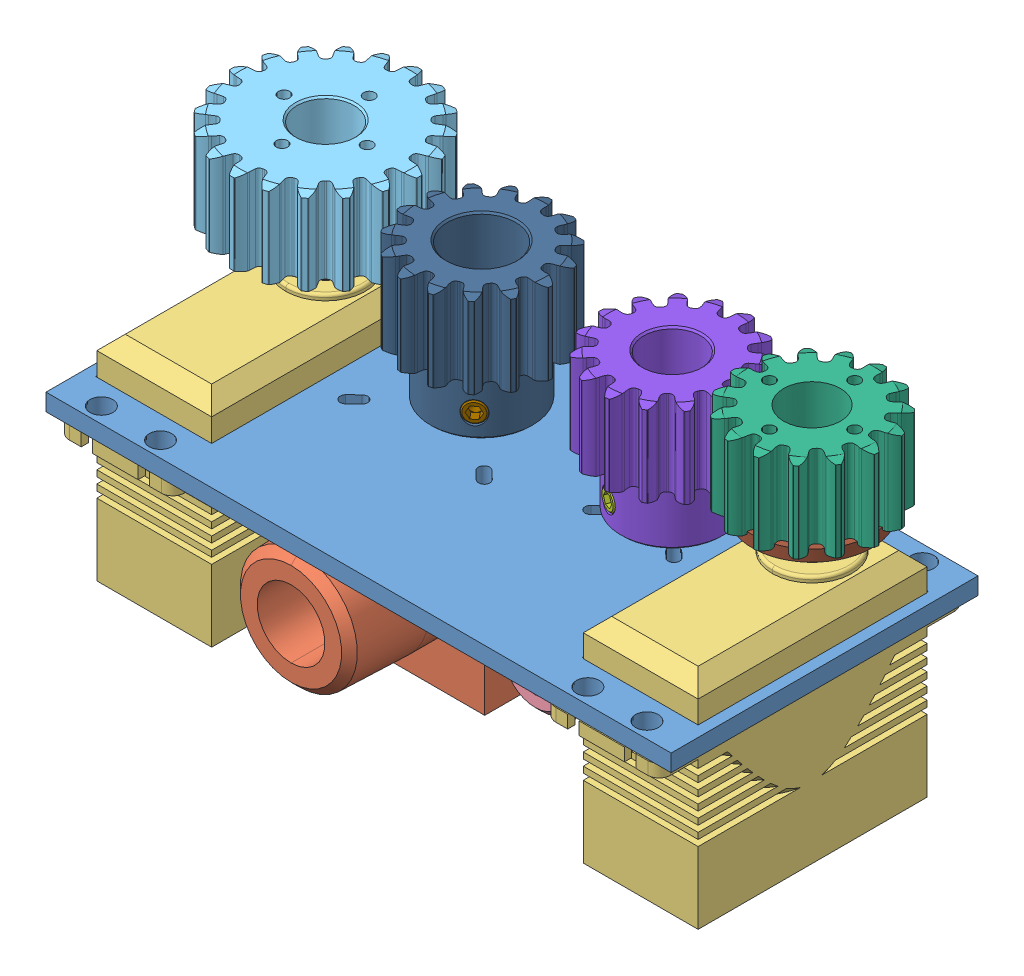
SolidWorks assembly assemblage vanne, configuration Défaut. Lengths in mm.
Overall size (115.02 63.08 70.73).
17 component instances, 11 part files, 19 mates.
Components (placement in the parent):
- support vanne servo-1: support vanne servo [Défaut] at (11.6117 -0.2898 118.0217) size (110 3 54)
- SS-8P6T2-SwagelokCompany-3D-11-16-2022-1: SS-8P6T2-SwagelokCompany-3D-11-16-2022 [Défaut] at (-2.7383 -31.2778 99.9999) x (0 0 1) z (0 1 0) size (67.06 28.45 46.75)
- Savox_SB2290SG Servo.stp-1: Savox_SB2290SG Servo.stp [Défaut] at (-30.1883 -2.5398 110) x (0 0 1) z (0 1 0) size (54 20.2 42.6)
- SS-4P4T2-SwagelokCompany-3D-11-16-2022-1: SS-4P4T2-SwagelokCompany-3D-11-16-2022 [Défaut] at (30.8117 -21.3718 99.9999) x (0 0 1) z (0 1 0) size (48.26 18.8 31.12)
- Savox_SB2290SG Servo.stp-3: Savox_SB2290SG Servo.stp [Défaut] at (55.6117 -2.5398 110.2) x (0 0 1) z (0 1 0) size (54 20.2 42.6)
- GEAB1.5-20-15-B-10 v1.step-1: GEAB1.5-20-15-B-10 v1.step [Défaut] at (-30.1884 31.7992 99.9999) x (1 0 0) z (0 -1 0) size (33 33 15.01)
  - GEAB1.5-20-15-B-10_b.step-1: GEAB1.5-20-15-B-10_b.step [Défaut] at origin size (33 33 15.01)
- GEAB1.5-15-15-B-10 v0.step-1: GEAB1.5-15-15-B-10 v0.step [Défaut] at (55.6116 16.3713 100.1999) x (1 0 0) z (0 1 0) size (25.44 25.39 15.01)
  - GEAB1.5-15-15-B-10_b.step-1: GEAB1.5-15-15-B-10_b.step [Défaut] at origin size (25.44 25.39 15.01)
- GEAB1.5-15-15-B-10.stp-1: GEAB1.5-15-15-B-10.stp [Défaut] at (30.8117 27.2102 99.9999) x (0.94768 0 0.319221) z (0 -1 0) size (25.44 25.39 24.01)
  - SET-SCREW4-4.stp-1: SET-SCREW4-4.stp [Défaut] at (0 5 20) x (0 -1 0) z (-1 0 0) size (4 4 4)
  - GEAB1.5-15-15-B-10_b.stp-1: GEAB1.5-15-15-B-10_b.stp [Défaut] at origin size (25.44 25.39 24.01)
- GEAB1.5-15-15-B-12.stp-1: GEAB1.5-15-15-B-12.stp [Défaut] at (-2.7383 27.2102 99.9999) x (0.774557 0 -0.632504) z (0 -1 0) size (25.44 25.39 24.01)
  - SET-SCREW4-3.stp-1: SET-SCREW4-3.stp [Défaut] at (0 6 20) x (0 -1 0) z (-1 0 0) size (3 4 4)
  - GEAB1.5-15-15-B-12_b.stp-1: GEAB1.5-15-15-B-12_b.stp [Défaut] at origin size (25.44 25.39 24.01)
- raccord servo v2.step-1: raccord servo v2.step [Défaut] at (65.6117 16.7992 100.1999) x (1 0 0) z (0 -1 0) size (21 21 7)
- raccord servo v2.step-2: raccord servo v2.step [Défaut] at (-20.1883 16.7992 99.9999) x (1 0 0) z (0 -1 0) size (21 21 7)
Mates (geometry in assembly coordinates):
- Coïncidente6: coincident anti-aligned: plane of support vanne servo-1 through (11.6117 -0.2898 118.0217) normal (0 -1 0); plane of SS-8P6T2-SwagelokCompany-3D-11-16-2022-1 through (-2.7383 -0.2898 99.9999) normal (0 1 0)
- Coaxiale1: concentric anti-aligned: cylinder of support vanne servo-1 through (-2.7383 -7.2898 99.9999) axis (0 1 0) radius 8; cylinder of SS-8P6T2-SwagelokCompany-3D-11-16-2022-1 through (-2.7383 15.4722 99.9999) axis (0 -1 0) radius 6
- Coïncidente9: coincident anti-aligned: plane of support vanne servo-1 through (11.6117 -0.2898 118.0217) normal (0 -1 0); plane of SS-4P4T2-SwagelokCompany-3D-11-16-2022-1 through (30.8117 -0.2898 99.9999) normal (0 1 0)
- Coaxiale2: concentric anti-aligned: cylinder of support vanne servo-1 through (30.8117 -12.2898 99.9999) axis (0 1 0) radius 6.5; cylinder of SS-4P4T2-SwagelokCompany-3D-11-16-2022-1 through (30.8117 9.7442 99.9999) axis (0 -1 0) radius 5
- Distance6: distance = 0.1 mm anti-aligned: plane of Savox_SB2290SG Servo.stp-3 through (65.7117 41.7771 154.7145) normal (1 0 0); plane of support vanne servo-1 through (65.6117 -43.2898 89.75) normal (-1 0 0)
- Distance7: distance = 0.1 mm anti-aligned: plane of support vanne servo-1 through (45.2117 -43.2898 130.25) normal (0 0 -1); plane of Savox_SB2290SG Servo.stp-3 through (31.7365 9.1602 130.35) normal (0 0 1)
- Parallèle2: parallel anti-aligned: plane of support vanne servo-1 through (11.6117 -0.2898 118.0217) normal (0 -1 0); plane of Savox_SB2290SG Servo.stp-3 through (31.7365 -0.2898 130.35) normal (0 1 0)
- Coïncidente10: coincident anti-aligned: plane of support vanne servo-1 through (11.6117 -0.2898 118.0217) normal (0 -1 0); plane of Savox_SB2290SG Servo.stp-3 through (31.7365 -0.2898 130.35) normal (0 1 0)
- Coaxiale3: concentric anti-aligned: cylinder of SS-4P4T2-SwagelokCompany-3D-11-16-2022-1 through (30.8117 9.7442 99.9999) axis (0 -1 0) radius 5; cylinder of GEAB1.5-15-15-B-10.stp-1/GEAB1.5-15-15-B-10_b.stp-1 through (30.8117 27.2102 99.9999) axis (0 1 0) radius 5
- Coaxiale4: concentric anti-aligned: cylinder of SS-8P6T2-SwagelokCompany-3D-11-16-2022-1 through (-2.7383 15.4722 99.9999) axis (0 -1 0) radius 6; cylinder of GEAB1.5-15-15-B-12.stp-1/GEAB1.5-15-15-B-12_b.stp-1 through (-2.7383 27.2102 99.9999) axis (0 1 0) radius 6
- Distance8: distance = 0.5 mm anti-aligned: plane of GEAB1.5-15-15-B-12.stp-1/GEAB1.5-15-15-B-12_b.stp-1 through (-2.7383 3.2102 99.9999) normal (0 -1 0); plane of support vanne servo-1 through (11.6117 2.7102 118.0217) normal (0 1 0)
- Distance9: distance = 0.5 mm anti-aligned: plane of support vanne servo-1 through (11.6117 2.7102 118.0217) normal (0 1 0); plane of GEAB1.5-15-15-B-10.stp-1/GEAB1.5-15-15-B-10_b.stp-1 through (30.8117 3.2102 99.9999) normal (0 -1 0)
- Coaxiale5: concentric anti-aligned: circle of raccord servo v2.step-1
- Coïncidente11: coincident anti-aligned: plane of Savox_SB2290SG Servo.stp-3 through (52.5039 14.1602 97.1047) normal (0 1 0); plane of raccord servo v2.step-2 through (-30.1806 14.1602 99.9994) normal (0 -1 0)
- Coaxiale7: concentric aligned: unknown of raccord servo v2.step-2
- Coïncidente12: coincident anti-aligned: plane of Savox_SB2290SG Servo.stp-3 through (52.5039 14.1602 97.1047) normal (0 1 0); plane of raccord servo v2.step-1 through (55.6194 14.1602 100.1994) normal (0 -1 0)
- Coaxiale8: concentric anti-aligned: cylinder of GEAB1.5-15-15-B-10 v0.step-1/GEAB1.5-15-15-B-10_b.step-1 through (55.6116 16.3713 100.1999) axis (0 -1 0) radius 5; cylinder of raccord servo v2.step-1 through (55.6116 9.7992 100.1999) axis (0 1 0) radius 1.5
- Coaxiale9: concentric anti-aligned: cylinder of GEAB1.5-20-15-B-10 v1.step-1/GEAB1.5-20-15-B-10_b.step-1 through (-30.1884 31.7992 99.9999) axis (0 1 0) radius 5; cylinder of raccord servo v2.step-2 through (-30.1884 16.7992 99.9999) axis (0 -1 0) radius 2.5
- Coïncidente13: coincident anti-aligned: plane of GEAB1.5-20-15-B-10 v1.step-1/GEAB1.5-20-15-B-10_b.step-1 through (-30.1884 16.7992 112.4999) normal (0 -1 0); plane of raccord servo v2.step-2 through (-30.1884 16.7992 99.9999) normal (0 1 0)
